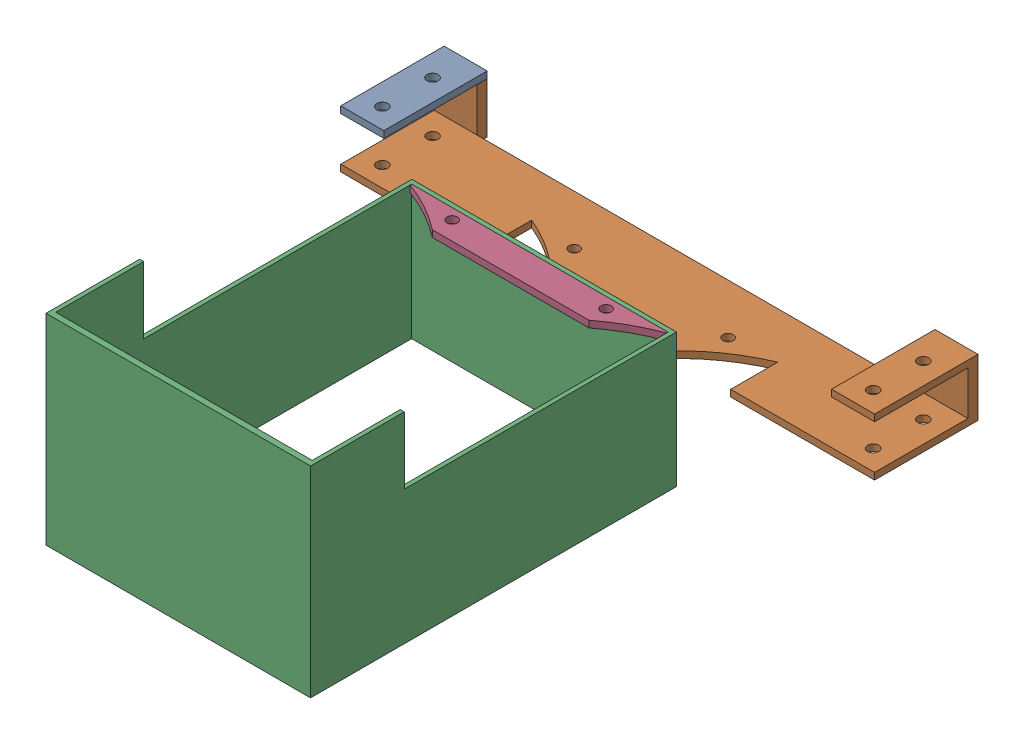
SolidWorks assembly anamontaj, configuration default. Lengths in mm.
Overall size (159.5 60 160.73).
2 component instances, 2 part files, 0 mates.
Components (placement in the parent):
- containerHolder-1: containerHolder [Default] at (561.3789 826.0794 1358.6441) size (159.5 17.1 30.9)
- mouth-1: mouth [Default] at (621.1665 853.3014 1350.2522) size (79.04 60 109.32)
